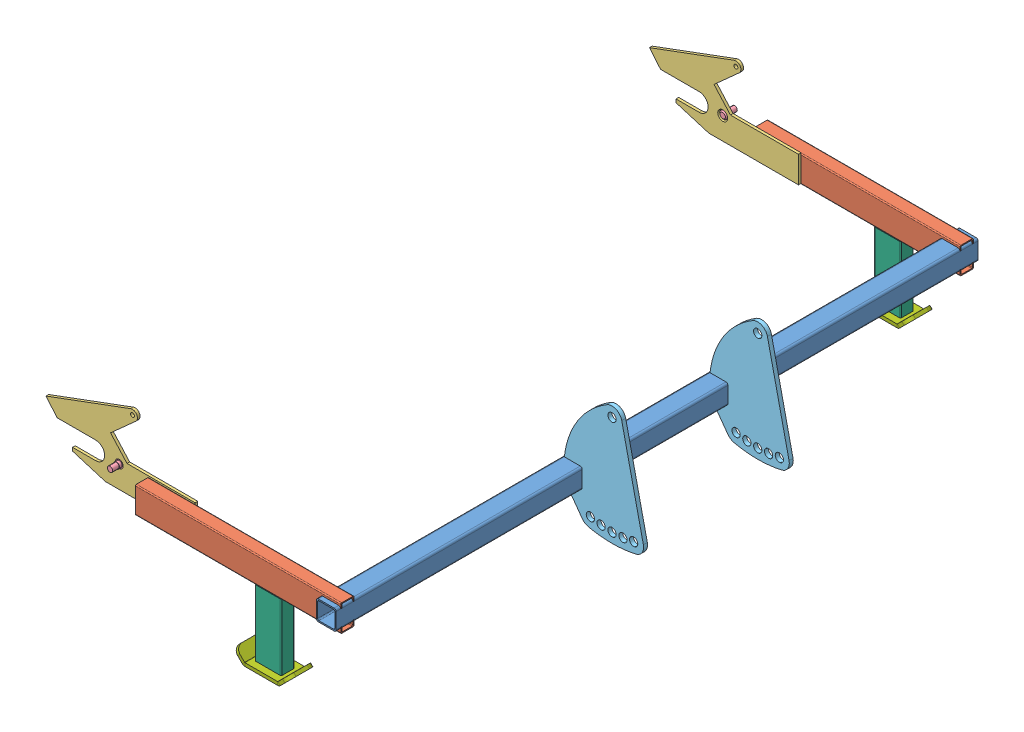
SolidWorks assembly ТП.016.10.01.00 - Силовой элемент рампы, configuration 00. Lengths in mm.
Overall size (557.77 243.25 975.2).
20 component instances, 7 part files, 6 mates.
Components (placement in the parent):
- ТП.016.10.01.01.00 - Рама рампы-1: ТП.016.10.01.01.00 - Рама рампы [00] at origin size (465.09 116.43 969.2)
  - ТП.016.10.01.01.01 - Поперечина рампы-1: ТП.016.10.01.01.01 - Поперечина рампы [--] at origin size (30 30 969.2)
  - ТП.016.10.01.01.02.00 - Боковина рампы с вилкой-1: ТП.016.10.01.01.02.00 - Боковина рампы с вилкой [Правая] at (-15 -20.75 457.6) x (0 0 -1) z (1 0 0) size (24 116.43 465.09)
    - ТП.016.10.01.01.02.01 - Боковина рампы-1: ТП.016.10.01.01.02.01 - Боковина рампы [--] at origin size (20 40 310)
    - ТП.016.10.01.01.02.02.00 - Вилка замка-1: ТП.016.10.01.01.02.02.00 - Вилка замка [Правая] at (4 35 -360) x (0 0 1) z (-1 0 0) size (225.09 114.93 18)
      - ТП.016.10.01.01.02.02.01 - Вилка навески (Ст3 S4мм)-1: ТП.016.10.01.01.02.02.01 - Вилка навески (Ст3 S4мм) [Правая] at origin size (225.09 114.93 4)
      - ТП.016.10.01.01.02.02.02 - Ось вилки навески-1: ТП.016.10.01.01.02.02.02 - Ось вилки навески [--] at (35.5 0 0) x (0.984194 0.177092 0) z (0 0 1) size (12 12 18)
  - ТП.016.10.01.01.02.00 - Боковина рампы с вилкой-2: ТП.016.10.01.01.02.00 - Боковина рампы с вилкой [Левая] at (-15 -20.75 -477.6) x (0 0 -1) z (1 0 0) size (24 116.43 465.09)
    - ТП.016.10.01.01.02.01 - Боковина рампы-1: ТП.016.10.01.01.02.01 - Боковина рампы [--] at origin size (20 40 310)
    - ТП.016.10.01.01.02.02.00 - Вилка замка-1: ТП.016.10.01.01.02.02.00 - Вилка замка [Левая] at (-20 35 -360) x (0 0 1) z (-1 0 0) size (225.09 114.93 18)
      - ТП.016.10.01.01.02.02.01 - Вилка навески (Ст3 S4мм)-1: ТП.016.10.01.01.02.02.01 - Вилка навески (Ст3 S4мм) [Левая] at origin size (225.09 114.93 4)
      - ТП.016.10.01.01.02.02.02 - Ось вилки навески-1: ТП.016.10.01.01.02.02.02 - Ось вилки навески [--] at (35.5 0 4) x (0.984194 -0.177092 0) z (0 0 -1) size (12 12 18)
- ТП.016.10.01.02 - Кронштейн рампы (Ст3 S-6мм)-1: ТП.016.10.01.02 - Кронштейн рампы (Ст3 S-6мм) [--] at (0 0 107) size (119.68 179.72 6)
- ТП.016.10.01.02 - Кронштейн рампы (Ст3 S-6мм)-2: ТП.016.10.01.02 - Кронштейн рампы (Ст3 S-6мм) [--] at (0 0 -113) size (119.68 179.72 6)
- ТП.016.10.01.03.00 - Нога-1: ТП.016.10.01.03.00 - Нога [00] at (-95 -120.75 467.6) size (85.36 105 40)
  - ТП.016.10.01.03.01 - Стойка-1: ТП.016.10.01.03.01 - Стойка [--] at origin size (40 100 20)
  - ТП.016.10.01.03.02 - Лыжа (Ст3 S-5мм)-1: ТП.016.10.01.03.02 - Лыжа (Ст3 S-5мм) [--] at origin size (85.36 19.14 40)
- ТП.016.10.01.03.00 - Нога-2: ТП.016.10.01.03.00 - Нога [00] at (-95 -120.75 -467.6) size (85.36 105 40)
  - ТП.016.10.01.03.01 - Стойка-1: ТП.016.10.01.03.01 - Стойка [--] at origin size (40 100 20)
  - ТП.016.10.01.03.02 - Лыжа (Ст3 S-5мм)-1: ТП.016.10.01.03.02 - Лыжа (Ст3 S-5мм) [--] at origin size (85.36 19.14 40)
Mates (geometry in assembly coordinates):
- Совпадение1: coincident: plane of ТП.016.10.01.01.00 - Рама рампы-1/ТП.016.10.01.01.01 - Поперечина рампы-1 through (15 12 527.0264) normal (1 0 0); plane of ТП.016.10.01.02 - Кронштейн рампы (Ст3 S-6мм)-1 through (15 12 113) normal (-1 0 0)
- Совпадение2: coincident: plane of ТП.016.10.01.01.00 - Рама рампы-1/ТП.016.10.01.01.01 - Поперечина рампы-1 through (-12 -15 527.0264) normal (0 -1 0); plane of ТП.016.10.01.02 - Кронштейн рампы (Ст3 S-6мм)-1 through (-12 -15 113) normal (0 1 0)
- Расстояние1: distance = 107 mm: point of assembly; plane of ТП.016.10.01.02 - Кронштейн рампы (Ст3 S-6мм)-1 through (27.2902 -43.6082 107) normal (0 0 -1)
- Совпадение3: coincident: plane of ТП.016.10.01.01.00 - Рама рампы-1/ТП.016.10.01.01.02.00 - Боковина рампы с вилкой-1/ТП.016.10.01.01.02.01 - Боковина рампы-1 through (-409.7214 -20.75 476.1) normal (0 -1 0); plane of ТП.016.10.01.03.00 - Нога-1/ТП.016.10.01.03.01 - Стойка-1 through (-76.5 -20.75 476.1) normal (0 1 0)
- Совпадение4: coincident: plane of ТП.016.10.01.01.00 - Рама рампы-1/ТП.016.10.01.01.02.00 - Боковина рампы с вилкой-1/ТП.016.10.01.01.02.01 - Боковина рампы-1 through (-409.7214 17.75 477.6) normal (0 0 1); plane of ТП.016.10.01.03.00 - Нога-1/ТП.016.10.01.03.01 - Стойка-1 through (-76.5 -20.75 477.6) normal (0 0 1)
- Расстояние2: distance = 90 mm: plane of ТП.016.10.01.03.00 - Нога-1/ТП.016.10.01.03.01 - Стойка-1 through (-75 -20.75 459.1) normal (1 0 0); plane of ТП.016.10.01.01.00 - Рама рампы-1/ТП.016.10.01.01.01 - Поперечина рампы-1 through (15 12 527.0264) normal (1 0 0)
